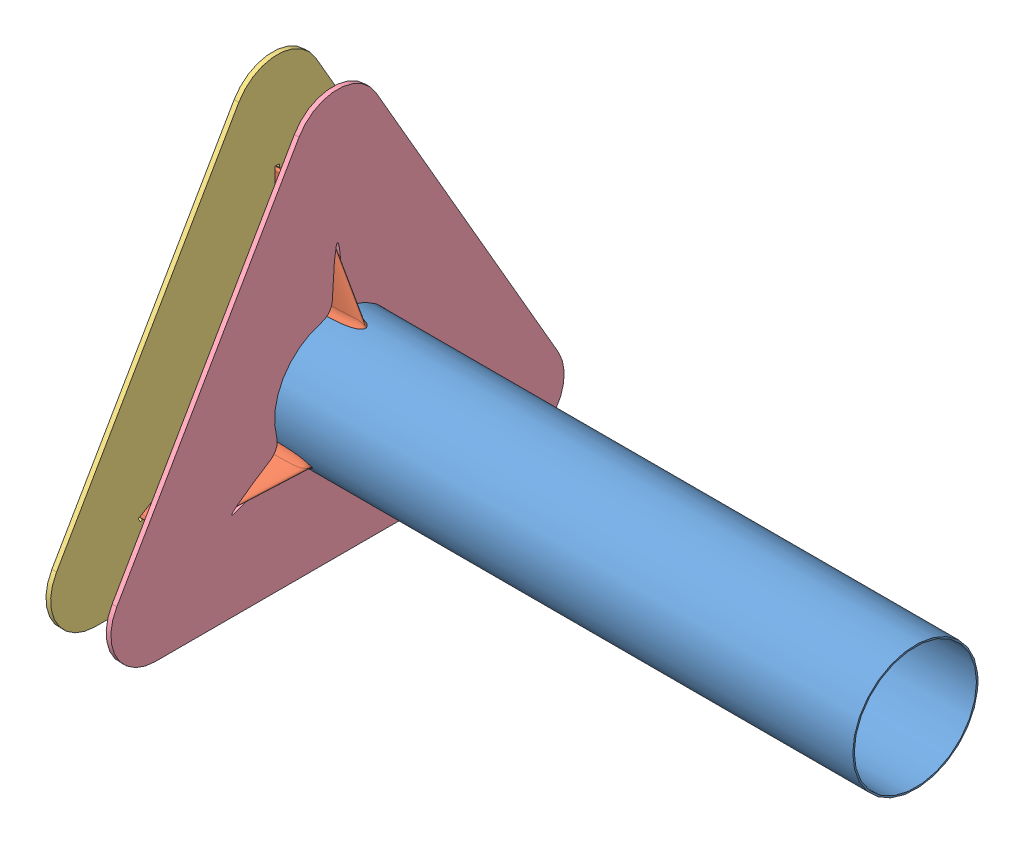
SolidWorks assembly Fin Jig Assem, configuration Default. Lengths in mm.
Overall size (940 803.25 779.12).
7 component instances, 4 part files, 6 mates.
Components (placement in the parent):
- Tube_Fin Assem-1: Tube_Fin Assem [Default] at (-355.7651 -513.0816 -737.1217) size (940 336.72 388.28)
  - Lower body tube-1: Lower body tube [Default] at (-139.4501 465.9697 748.9517) size (940 169.1 169.1)
  - Fin 150_75_145 curved-1: Fin 150_75_145 curved [Default] at (60.6814 545.4697 748.9517) x (-1 0 0) z (0 1 0) size (161.53 40.42 136.76)
  - Fin 150_75_145 curved-2: Fin 150_75_145 curved [Default] at (60.6814 426.2197 817.8008) x (-1 0 0) z (0 -0.5 0.866025) size (161.53 40.42 136.76)
  - Fin 150_75_145 curved-3: Fin 150_75_145 curved [Default] at (60.6814 426.2197 680.1027) x (-1 0 0) z (0 -0.5 -0.866025) size (161.53 40.42 136.76)
- Back-1: Back [Default] at (-416.8653 -249.1845 -338.1699) x (0 0.866025 -0.5) z (0 0.5 0.866025) size (612.15 6.35 546.22)
- Front-1: Front [Default] at (-335.5153 -249.1845 -338.1699) x (0 0.866025 -0.5) z (0 0.5 0.866025) size (612.15 6.35 546.22)
Mates (geometry in assembly coordinates):
- Concentric1: concentric aligned: cylinder of Tube_Fin Assem-1/Lower body tube-1 through (444.7847 -47.1119 11.8301) axis (-1 0 0) radius 84.55; cylinder of Back-1 through (-416.8653 -47.1119 11.8301) axis (-1 0 0) radius 85
- Parallel1: parallel anti-aligned: plane of Tube_Fin Assem-1/Fin 150_75_145 curved-1 through (-370.0747 165.3881 11.8301) normal (0 1 0); plane of Back-1 through (-416.8653 167.8881 8.8301) normal (0 -1 0)
- Concentric2: concentric aligned: cylinder of Tube_Fin Assem-1/Lower body tube-1 through (444.7847 -47.1119 11.8301) axis (-1 0 0) radius 84.55; cylinder of Front-1 through (-335.5153 -47.1119 11.8301) axis (-1 0 0) radius 85
- Coincident2: coincident aligned: plane of Back-1 through (-423.2153 -249.1845 361.8301) normal (0 0.5 0.866025); plane of Front-1 through (-341.8653 -249.1845 361.8301) normal (0 0.5 0.866025)
- Distance1: distance = 75 mm anti-aligned: plane of Back-1 through (-416.8653 -249.1845 -338.1699) normal (1 0 0); plane of Front-1 through (-341.8653 -249.1845 -338.1699) normal (-1 0 0)
- Distance2: distance = 72 mm aligned: plane of Back-1 through (-423.2153 -249.1845 -338.1699) normal (-1 0 0); plane of Tube_Fin Assem-1/Lower body tube-1 through (-495.2153 -47.1119 11.8301) normal (-1 0 0)
